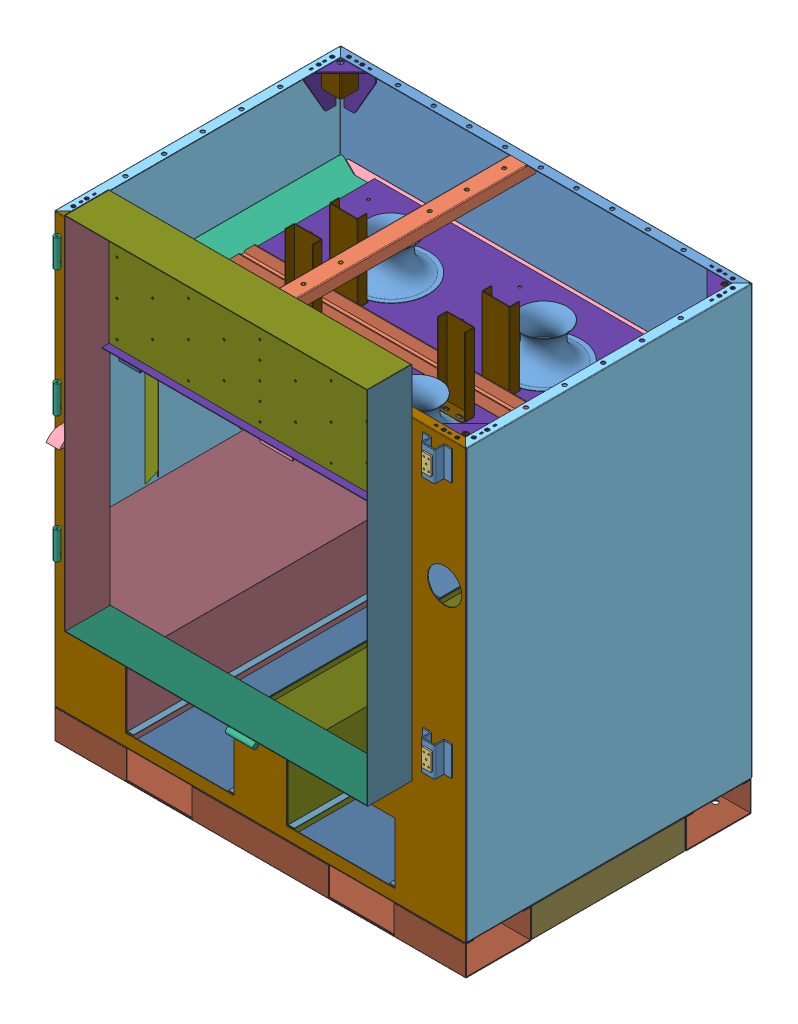
SolidWorks assembly 主機, configuration 預設. Lengths in mm.
Overall size (1423.04 1696.79 1110.69).
127 component instances, 43 part files, 85 mates.
Components (placement in the parent):
- 機體後板-1: 機體後板 [預設] at (-41.0813 66.5472 -21.748) size (1380 1438.1 45.5)
  - LB-A54A-02-6-1: LB-A54A-02-6 [預設] at (-80618.6768 10088.9698 -1) size (1380 1438.1 34.19)
  - LB-A54A-02-7-1: LB-A54A-02-7 [預設] at (654.2438 -32.1294 19.8) x (-1 0 0) z (0 0 -1) size (1360 70.4 18.8)
  - LB-A54-03-4-1: LB-A54-03-4 [預設] at (-510.6908 -452.7134 1) size (443.37 51.57 20.58)
  - LB-A54-03-4-2: LB-A54-03-4 [預設] at (39.1118 -452.7134 1) size (443.37 51.57 20.58)
  - LB-A54A-02-8-1: LB-A54A-02-8 [預設] at (-85867.9995 11163.7201 1) size (1352 43.5 43.5)
- 機體左板-1: 機體左板 [預設] at (-750.0294 157.4231 409.053) x (0 0 -1) z (1 0 0) size (956 1468.3 173.55)
  - LB-A54A-02-25-1: LB-A54A-02-25 [預設] at (-80501.2269 12822.4182 -1) size (956 1468.3 34.19)
  - LB-A54A-02-9-1: LB-A54A-02-9 [預設] at (-520.391 339.3107 -46.78) x (1 0 0) z (0 -1 0) size (948 152.22 53.22)
  - LB-A54A-02-23-1: LB-A54A-02-23 [預設] at (-186.4707 336.0907 45.7599) x (0 -1 0) z (0.707107 0 -0.707107) size (628.6 32.46 32.46)
  - LB-A54A-02-23-2: LB-A54A-02-23 [預設] at (133.5293 336.0907 45.7599) x (0 -1 0) z (0.707107 0 -0.707107) size (628.6 32.46 32.46)
  - LB-A54A-02-24-1: LB-A54A-02-24 [預設] at (-234.3113 -777.1798 45.7599) x (0 1 0) z (-0.707107 0 -0.707107) size (465.6 32.46 32.46)
  - LB-A54A-02-24-2: LB-A54A-02-24 [預設] at (85.6887 -777.1798 45.7599) x (0 1 0) z (-0.707107 0 -0.707107) size (465.6 32.46 32.46)
- LB-A54A-02-1-1: LB-A54A-02-1 [預設] at (631.1626 -630.0662 939.544) x (-1 0 0) z (0 0 -1) size (1380 1440 32.1)
- 機體左板-2: 機體左板 [預設] at (632.3545 157.4231 509.835) x (0 0 1) z (-1 0 0) size (956 1468.3 173.55)
  - LB-A54A-02-25-1: LB-A54A-02-25 [預設] at (-80501.2269 12822.4182 -1) size (956 1468.3 34.19)
  - LB-A54A-02-9-1: LB-A54A-02-9 [預設] at (-520.391 339.3107 -46.78) x (1 0 0) z (0 -1 0) size (948 152.22 53.22)
  - LB-A54A-02-23-1: LB-A54A-02-23 [預設] at (-186.4707 336.0907 45.7599) x (0 -1 0) z (0.707107 0 -0.707107) size (628.6 32.46 32.46)
  - LB-A54A-02-23-2: LB-A54A-02-23 [預設] at (133.5293 336.0907 45.7599) x (0 -1 0) z (0.707107 0 -0.707107) size (628.6 32.46 32.46)
  - LB-A54A-02-24-1: LB-A54A-02-24 [預設] at (-234.3113 -777.1798 45.7599) x (0 1 0) z (-0.707107 0 -0.707107) size (465.6 32.46 32.46)
  - LB-A54A-02-24-2: LB-A54A-02-24 [預設] at (85.6887 -777.1798 45.7599) x (0 1 0) z (-0.707107 0 -0.707107) size (465.6 32.46 32.46)
- 底板-1: 底板 [預設] at (-68.9419 -631.2162 474.3961) x (1 0 0) z (0 -1 0) size (1380.01 960 103.29)
  - LB-A54A-02-26-1: LB-A54A-02-26 [預設] at (-83868.7741 4779.2866 -1.15) size (1380 960 2.3)
  - LB-A54-01-1-1: LB-A54-01-1 [預設] at (-4146.7623 -34163.5866 99.142) size (1380 221 100.99)
  - LB-A54-01-1-2: LB-A54-01-1 [預設] at (4166.9713 34133.8822 99.142) x (-1 0 0) z (0 0 1) size (1380 221 100.99)
  - LB-A54A-02-48-1: LB-A54A-02-48 [預設] at (-5795.5581 81855.4362 102.142) x (0 -1 0) z (0 0 -1) size (517 187 100.99)
  - LB-A54A-02-48-2: LB-A54A-02-48 [預設] at (-5204.2988 81856.4362 102.142) x (0 -1 0) z (0 0 -1) size (517 187 100.99)
  - LB-A54A-02-48-3: LB-A54A-02-48 [預設] at (-4602.5501 81856.4362 102.142) x (0 -1 0) z (0 0 -1) size (517 187 100.99)
- 抽屜導板-1-1: 抽屜導板-1 [預設] at (-629.1921 -325.5931 429.5209) x (0 0 -1) z (1 0 0) size (956 485.93 257.9)
  - LB-A54A-02-27-1: LB-A54A-02-27 [預設] at (-79953.6583 17617.1683 116.5034) size (956 485.93 236.21)
  - LB-A54-10-4-1: LB-A54-10-4 [預設] at (-85291.4913 17401.3144 118.1034) size (955 14.7 21.69)
- 抽屜導板-1-2: 抽屜導板-1 [預設] at (511.5173 -325.5931 484.9831) x (0 0 1) z (-1 0 0) size (956 485.93 257.9)
  - LB-A54A-02-27-1: LB-A54A-02-27 [預設] at (-79953.6583 17617.1683 116.5034) size (956 485.93 236.21)
  - LB-A54-10-4-1: LB-A54-10-4 [預設] at (-85291.4913 17401.3144 118.1034) size (955 14.7 21.69)
- 抽屜導板-2-1: 抽屜導板-2 [預設] at (-103.4633 -459.7341 455.609) x (0 0 1) z (-1 0 0) size (956 387.73 110.27)
  - LB-A54A-02-28-1: LB-A54A-02-28 [預設] at (-81709.8281 17694.6839 42.6882) size (956 387.73 88.58)
  - LB-A54-10-4-1: LB-A54-10-4 [預設] at (-85262.1171 17534.7927 44.2882) size (955 14.7 21.69)
- 抽屜導板-3-1: 抽屜導板-3 [預設] at (-14.2116 -436.2348 485.6989) x (0 0 -1) z (1 0 0) size (956 387.73 110.27)
  - LB-A54A-02-29-1: LB-A54A-02-29 [預設] at (-83501.0241 17671.1846 42.6882) size (956 387.73 88.58)
  - LB-A54-10-4-1: LB-A54-10-4 [預設] at (-85236.3132 17511.2933 44.2882) size (955 14.7 21.69)
- 濾材風箱-1-1: 濾材風箱-1 [預設] at (-7.9679 507.4838 538.2077) x (1 0 0) z (0 1 0) size (1128.4 969.2 262.16)
  - LB-A54A-02-11-1: LB-A54A-02-11 [預設] at (-609.5195 -443.3362 -10.75) size (1128.4 969.2 21.5)
  - LB-A54-07-4-1: LB-A54-07-4 [預設] at (-382.2595 134.0628 -46.99) x (0 0 1) z (0 1 0) size (260.16 94.4 42.16)
  - LB-A54-07-4-2: LB-A54-07-4 [預設] at (129.7405 134.0628 -46.99) x (0 0 1) z (0 1 0) size (260.16 94.4 42.16)
  - LB-A54-07-4-3: LB-A54-07-4 [預設] at (-231.4595 17.0628 -46.99) x (0 0 1) z (0 -1 0) size (260.16 94.4 42.16)
  - LB-A54-07-4-4: LB-A54-07-4 [預設] at (280.5405 17.0628 -46.99) x (0 0 1) z (0 -1 0) size (260.16 94.4 42.16)
  - 250文氏管-1: 250文氏管 [預設] at (-422.6898 248.1172 -8.75) x (0.927762 0.373172 0) z (0.373172 -0.927762 0) size (250 120 250)
  - 250文氏管-2: 250文氏管 [預設] at (90.1102 248.1172 -8.75) x (0.927762 0.373172 0) z (0.373172 -0.927762 0) size (250 120 250)
  - 250文氏管-3: 250文氏管 [預設] at (-422.6898 -178.8828 -8.75) x (0.927762 0.373172 0) z (0.373172 -0.927762 0) size (250 120 250)
  - 250文氏管-4: 250文氏管 [預設] at (90.1102 -178.8828 -8.75) x (0.927762 0.373172 0) z (0.373172 -0.927762 0) size (250 120 250)
  - LB-A54A-02-12-2: LB-A54A-02-12 [預設] at (-84291.9278 16147.3106 -8.75) size (1128.4 55 40.99)
- 凸輪軌道座-中-1: 凸輪軌道座-中 [預設] at (-58.2874 410.5301 355.1892) x (0 0 -1) z (1 0 0) size (856 69.59 110.4)
  - LB-A54-12-2-1: LB-A54-12-2 [預設] at (-530.5548 -8.8562 -24.71) size (856 68.08 109.86)
  - LB-A54-12-8-1: LB-A54-12-8 [預設] at (-530.5548 17.0438 55.01) x (0 0 -1) z (1 0 0) size (110.2 69 3)
  - LB-A54-12-7-2: LB-A54-12-7 [預設] at (325.4452 17.2038 -54.99) x (0 0 1) z (-1 0 0) size (110.2 69 3)
  - LB-A54-12-9-1: LB-A54-12-9 [預設] at (-245.0548 17.4038 52.63) x (0 0 -1) z (1 0 0) size (104.6 66.5 3)
  - LB-A54-12-9-2: LB-A54-12-9 [預設] at (39.9452 17.4038 52.63) x (0 0 -1) z (1 0 0) size (104.6 66.5 3)
  - 2分半點焊螺帽-1: 2分半點焊螺帽 [預設] at (-492.5548 78.7038 0) x (-0.002666 0 -0.999996) z (0.999996 0 -0.002666) size (18.22 7.93 18.22)
  - 2分半點焊螺帽-2: 2分半點焊螺帽 [預設] at (-297.5548 78.7038 0) x (-0.002666 0 -0.999996) z (0.999996 0 -0.002666) size (18.22 7.93 18.22)
  - 2分半點焊螺帽-3: 2分半點焊螺帽 [預設] at (-102.5548 78.7038 0) x (-0.002666 0 -0.999996) z (0.999996 0 -0.002666) size (18.22 7.93 18.22)
  - 2分半點焊螺帽-4: 2分半點焊螺帽 [預設] at (92.4452 78.7038 0) x (-0.002666 0 -0.999996) z (0.999996 0 -0.002666) size (18.22 7.93 18.22)
  - 2分半點焊螺帽-5: 2分半點焊螺帽 [預設] at (287.4452 78.7038 0) x (-0.002666 0 -0.999996) z (0.999996 0 -0.002666) size (18.22 7.93 18.22)
- 凸輪軌道座-左-1: 凸輪軌道座-左 [預設] at (-551.6774 443.4947 508.4972) x (0 0 1) z (-1 0 0) size (856 69.43 71.3)
  - LB-A54-12-1-1: LB-A54-12-1 [預設] at (-478.7533 -41.8208 -5.1) size (856 68.08 70.64)
  - LB-A54-12-4-1: LB-A54-12-4 [預設] at (-478.7533 -15.7608 35.7) x (0 0 -1) z (1 0 0) size (71.3 69 3)
  - LB-A54-12-5-1: LB-A54-12-5 [預設] at (374.2467 -15.7608 35.7) x (0 0 -1) z (1 0 0) size (71.3 69 3)
  - LB-A54-12-6-1: LB-A54-12-6 [預設] at (90.2467 -14.8808 35.4) x (0 0 -1) z (1 0 0) size (68.5 66.5 3)
  - LB-A54-12-6-2: LB-A54-12-6 [預設] at (-194.7533 -14.8808 35.4) x (0 0 -1) z (1 0 0) size (68.5 66.5 3)
  - 2分半點焊螺帽-1: 2分半點焊螺帽 [預設] at (-440.7533 45.7392 15.11) size (18.22 7.93 18.22)
  - 2分半點焊螺帽-2: 2分半點焊螺帽 [預設] at (-245.7533 45.7392 15.11) size (18.22 7.93 18.22)
  - 2分半點焊螺帽-3: 2分半點焊螺帽 [預設] at (-50.7533 45.7392 15.11) size (18.22 7.93 18.22)
  - 2分半點焊螺帽-4: 2分半點焊螺帽 [預設] at (144.2467 45.7392 15.11) size (18.22 7.93 18.22)
  - 2分半點焊螺帽-5: 2分半點焊螺帽 [預設] at (339.2467 45.7392 15.11) size (18.22 7.93 18.22)
- 凸輪軌道座-右-1: 凸輪軌道座-右 [預設] at (435.1026 473.5613 463.8637) x (0 0 -1) z (1 0 0) size (856 69.43 71.7)
  - LB-A54-12-3-1: LB-A54-12-3 [預設] at (-421.8803 -71.8874 -5.1) size (856 68.08 70.64)
  - LB-A54-12-4-1: LB-A54-12-4 [預設] at (431.1197 -45.8274 36.1) x (0 0 -1) z (1 0 0) size (71.3 69 3)
  - LB-A54-12-5-1: LB-A54-12-5 [預設] at (-421.8803 -45.8274 35.7) x (0 0 -1) z (1 0 0) size (71.3 69 3)
  - LB-A54-12-6-1: LB-A54-12-6 [預設] at (147.1197 -44.9474 35.4) x (0 0 -1) z (1 0 0) size (68.5 66.5 3)
  - LB-A54-12-6-2: LB-A54-12-6 [預設] at (-137.8803 -44.9474 35.4) x (0 0 -1) z (1 0 0) size (68.5 66.5 3)
  - 2分半點焊螺帽-1: 2分半點焊螺帽 [預設] at (-383.8803 15.6726 15.11) size (18.22 7.93 18.22)
  - 2分半點焊螺帽-2: 2分半點焊螺帽 [預設] at (-188.8803 15.6726 15.11) size (18.22 7.93 18.22)
  - 2分半點焊螺帽-3: 2分半點焊螺帽 [預設] at (6.1197 15.6726 15.11) size (18.22 7.93 18.22)
  - 2分半點焊螺帽-4: 2分半點焊螺帽 [預設] at (201.1197 15.6726 15.11) size (18.22 7.93 18.22)
  - 2分半點焊螺帽-5: 2分半點焊螺帽 [預設] at (396.1197 15.6726 15.11) size (18.22 7.93 18.22)
- LB-A54A-02-2-1: LB-A54A-02-2 [預設] at (-567.7375 -248.8662 922.444) x (0 1 0) z (1 0 0) size (1212.3 152.4 16.9)
- LB-A54A-02-3-1: LB-A54A-02-3 [預設] at (448.8626 -248.8662 922.444) x (0 1 0) z (1 0 0) size (1212.3 152.4 16.9)
- LB-A54A-02-4-1: LB-A54A-02-4 [預設] at (-565.1374 -246.8662 922.1663) x (1 0 0) z (0 -1 0) size (1014 152.38 17.18)
- LB-A54A-02-5-1: LB-A54A-02-5 [預設] at (-565.1374 515.4561 939.544) size (1014 447.98 148.38)
- 連接補強座-1-1: 連接補強座-1 [預設] at (-753.2212 727.2428 -2.373) x (0 0 -1) z (0 -1 0) size (120.61 124.61 161.4)
  - LB-A54A-02-32-1: LB-A54A-02-32 [預設] at (-84294.0927 8119.5382 -80.691) size (120.61 124.61 161.4)
  - LB-A54-02-5-1: LB-A54-02-5 [預設] at (-51.817 10.2837 -76.691) x (0 1 0) z (1 0 0) size (64.1 80 64.1)
- 連接補強座-1-2: 連接補強座-1 [預設] at (612.9795 727.2428 -24.9398) x (1 0 0) z (0 -1 0) size (120.61 124.61 161.4)
  - LB-A54A-02-32-1: LB-A54A-02-32 [預設] at (-84294.0927 8119.5382 -80.691) size (120.61 124.61 161.4)
  - LB-A54-02-5-1: LB-A54-02-5 [預設] at (-51.817 10.2837 -76.691) x (0 1 0) z (1 0 0) size (64.1 80 64.1)
- 連接補強座-1-3: 連接補強座-1 [預設] at (-730.6544 727.2428 943.8277) x (-1 0 0) z (0 -1 0) size (120.61 124.61 161.4)
  - LB-A54A-02-32-1: LB-A54A-02-32 [預設] at (-84294.0927 8119.5382 -80.691) size (120.61 124.61 161.4)
  - LB-A54-02-5-1: LB-A54-02-5 [預設] at (-51.817 10.2837 -76.691) x (0 1 0) z (1 0 0) size (64.1 80 64.1)
- 連接補強座-1-4: 連接補強座-1 [預設] at (635.5463 727.2428 921.2609) x (0 0 1) z (0 -1 0) size (120.61 124.61 161.4)
  - LB-A54A-02-32-1: LB-A54A-02-32 [預設] at (-84294.0927 8119.5382 -80.691) size (120.61 124.61 161.4)
  - LB-A54-02-5-1: LB-A54-02-5 [預設] at (-51.817 10.2837 -76.691) x (0 1 0) z (1 0 0) size (64.1 80 64.1)
- FE2100LZ-54-47-2-1: FE2100LZ-54-47-2 [預設] at (613.0545 688.8338 974.744) x (-1 0 0) z (0 0 -1) size (97.2 98 35.2)
- FE2100LZ-54-47-2-2: FE2100LZ-54-47-2 [預設] at (613.0545 -171.1662 974.744) x (-1 0 0) z (0 0 -1) size (97.2 98 35.2)
- 機體-補強1-1: 機體-補強1 [預設] at (-132.7621 791.0738 490.8283) x (0 0 -1) z (0 -1 0) size (954 60.44 38.15)
  - LB-A54A-02-43-1: LB-A54A-02-43 [預設] at (-445.6157 -48.5473 -18.86) size (954 60.44 37.72)
  - 2分半點焊螺帽-1: 2分半點焊螺帽 [預設] at (-368.1832 13.9527 -11.36) x (1 0 0) z (0 1 0) size (18.22 7.93 18.22)
  - 2分半點焊螺帽-2: 2分半點焊螺帽 [預設] at (-243.1832 13.9527 -11.36) x (1 0 0) z (0 1 0) size (18.22 7.93 18.22)
  - 2分半點焊螺帽-3: 2分半點焊螺帽 [預設] at (-118.1832 13.9527 -11.36) x (1 0 0) z (0 1 0) size (18.22 7.93 18.22)
  - 2分半點焊螺帽-4: 2分半點焊螺帽 [預設] at (430.9519 13.9527 -11.36) x (1 0 0) z (0 1 0) size (18.22 7.93 18.22)
  - 2分半點焊螺帽-5: 2分半點焊螺帽 [預設] at (305.9519 13.9527 -11.36) x (1 0 0) z (0 1 0) size (18.22 7.93 18.22)
  - 2分半點焊螺帽-6: 2分半點焊螺帽 [預設] at (180.9519 13.9527 -11.36) x (1 0 0) z (0 1 0) size (18.22 7.93 18.22)
- LB-A54A-02-30-1: LB-A54A-02-30 [預設] at (555.7545 768.3338 979.744) x (0 -1 0) z (0 0 -1) size (61 33 5)
- LB-A54A-02-30-2: LB-A54A-02-30 [預設] at (555.7545 -91.6662 979.744) x (0 -1 0) z (0 0 -1) size (61 33 5)
- 撐座1-1: 撐座1 [預設] at (-671.5374 -29294.2198 153782.015) x (0 0 -1) z (1 0 0) size (106.64 28 45)
- LB-A54-02-3-3: LB-A54-02-3 [預設] at (-510.0888 -368.0662 937.544) x (1 0 0) z (0 0 -1) size (363 19.1 19.1)
- LB-A54-02-3-4: LB-A54-02-3 [預設] at (30.4138 -368.0662 937.544) x (1 0 0) z (0 0 -1) size (363 19.1 19.1)
- 釘雙座-1: 釘雙座 [預設] at (-659.4122 755.0376 966.2275) size (19.4 93 19.4)
  - 門蓋丁雙固定座-1: 門蓋丁雙固定座 [預設] at (-112.9585 -46.1037 23.6835) (suppressed, hidden)
  - 釘雙-1: 釘雙 [預設] at (-19.1747 49.3962 36.1835) x (0.021323 0 -0.999773) z (0 -1 0) size (19 19 93)
- 釘雙座-2: 釘雙座 [預設] at (-659.4122 330.0376 966.2275) size (19.4 93 19.4)
  - 門蓋丁雙固定座-1: 門蓋丁雙固定座 [預設] at (-112.9585 -46.1037 23.6835) (suppressed, hidden)
  - 釘雙-1: 釘雙 [預設] at (-19.1747 49.3962 36.1835) x (0.021323 0 -0.999773) z (0 -1 0) size (19 19 93)
- 釘雙座-3: 釘雙座 [預設] at (-659.4122 -94.9624 966.2275) size (19.4 93 19.4)
  - 門蓋丁雙固定座-1: 門蓋丁雙固定座 [預設] at (-112.9585 -46.1037 23.6835) (suppressed, hidden)
  - 釘雙-1: 釘雙 [預設] at (-19.1747 49.3962 36.1835) x (0.021323 0 -0.999773) z (0 -1 0) size (19 19 93)
- 釘雙座-4: 釘雙座 [預設] at (-54.1412 -327.7751 966.2275) x (0 1 0) z (0 0 1) size (19.4 93 19.4)
  - 門蓋丁雙固定座-1: 門蓋丁雙固定座 [預設] at (-112.9585 -46.1037 23.6835) (suppressed, hidden)
  - 釘雙-1: 釘雙 [預設] at (-19.1747 49.3962 36.1835) x (0.021323 0 -0.999773) z (0 -1 0) size (19 19 93)
Mates (geometry in assembly coordinates):
- 重合/共線/共點1: coincident aligned: plane of 機體後板-1/LB-A54A-02-6-1 through (-748.8374 809.9338 -1456.856) normal (0 1 0); plane of 機體左板-1/LB-A54A-02-25-1 through (-2185.1374 809.9338 937.444) normal (0 1 0)
- 重合/共線/共點2: coincident anti-aligned: plane of 機體後板-1/LB-A54A-02-6-1 through (-716.8374 807.9338 11.444) normal (-0.707107 0 0.707107); plane of 機體左板-1/LB-A54A-02-25-1 through (-716.8374 807.9338 11.444) normal (0.707107 0 -0.707107)
- 重合/共線/共點3: coincident: line of 機體後板-1/LB-A54A-02-6-1 through (-716.8374 807.9338 11.444) axis (0 1 0); point of 機體左板-1/LB-A54A-02-25-1
- 重合/共線/共點4: coincident aligned: plane of 機體左板-1/LB-A54A-02-25-1 through (-2185.1374 809.9338 937.444) normal (0 1 0); plane of LB-A54A-02-1-1 through (626.1626 809.9338 938.144) normal (0 1 0)
- 重合/共線/共點5: coincident anti-aligned: plane of 機體左板-1/LB-A54A-02-25-1 through (-716.8374 807.9338 907.444) normal (0.707107 0 0.707107); plane of LB-A54A-02-1-1 through (-746.5374 807.9338 937.144) normal (-0.707107 0 -0.707107)
- 重合/共線/共點6: coincident: line of 機體左板-1/LB-A54A-02-25-1 through (-746.5374 807.9338 937.144) axis (0 1 0); point of LB-A54A-02-1-1
- 重合/共線/共點7: coincident aligned: plane of 機體後板-1/LB-A54A-02-6-1 through (-748.8374 809.9338 -1456.856) normal (0 1 0); plane of 機體左板-2/LB-A54A-02-25-1 through (2067.4625 809.9338 -18.556) normal (0 1 0)
- 重合/共線/共點8: coincident anti-aligned: plane of 機體後板-1/LB-A54A-02-6-1 through (599.1625 807.9338 11.444) normal (0.707107 0 0.707107); plane of 機體左板-2/LB-A54A-02-25-1 through (599.1625 807.9338 11.444) normal (-0.707107 0 -0.707107)
- 重合/共線/共點9: coincident: line of 機體後板-1/LB-A54A-02-6-1 through (599.1625 807.9338 11.444) axis (0 1 0); point of 機體左板-2/LB-A54A-02-25-1
- 重合/共線/共點10: coincident anti-aligned: plane of LB-A54A-02-1-1 through (631.1626 -630.0662 937.544) normal (0 -1 0); plane of 底板-1/LB-A54A-02-26-1 through (-748.8374 -630.0662 -20.456) normal (0 1 0)
- 重合/共線/共點11: coincident aligned: plane of LB-A54A-02-1-1 through (626.1626 807.5338 939.544) normal (0 0 1); plane of 底板-1/LB-A54A-02-26-1 through (631.1626 -632.3662 939.544) normal (0 0 1)
- 重合/共線/共點12: coincident aligned: plane of 機體後板-1/LB-A54A-02-6-1 through (-748.8374 -628.1662 -20.748) normal (-1 0 0); plane of 底板-1/LB-A54A-02-26-1 through (-748.8374 -632.3662 939.544) normal (-1 0 0)
- 重合/共線/共點13: coincident anti-aligned: plane of 機體後板-1/LB-A54A-02-6-1 through (-748.8374 -628.1662 -20.748) normal (0 0 1); plane of 抽屜導板-1-1/LB-A54A-02-27-1 through (-511.0887 -377.7495 -20.748) normal (0 0 -1)
- 重合/共線/共點14: coincident: line of 機體後板-1/LB-A54A-02-6-1 through (-745.7061 -142.1322 -22.748) axis (0.707107 -0.707107 0); plane of 抽屜導板-1-1/LB-A54A-02-27-1 through (-512.0195 -375.8188 -20.748) normal (0.707107 0.707107 0)
- 重合/共線/共點15: coincident: line of 機體後板-1/LB-A54A-02-6-1 through (-511.0887 -376.7495 -22.748) axis (0 -1 0); plane of 抽屜導板-1-1/LB-A54A-02-27-1 through (-511.0887 -376.7495 -20.748) normal (1 0 0)
- 重合/共線/共點16: coincident anti-aligned: plane of 機體後板-1/LB-A54A-02-6-1 through (-748.8374 -628.1662 -20.748) normal (0 0 1); plane of 抽屜導板-1-2/LB-A54A-02-27-1 through (624.9578 -145.2056 -20.748) normal (0 0 -1)
- 重合/共線/共點17: coincident: line of 機體後板-1/LB-A54A-02-6-1 through (628.0312 -142.1322 -22.748) axis (-0.707107 -0.707107 0); plane of 抽屜導板-1-2/LB-A54A-02-27-1 through (394.3446 -375.8188 935.252) normal (-0.707107 0.707107 0)
- 重合/共線/共點18: coincident: line of 機體後板-1/LB-A54A-02-6-1 through (393.4139 -376.7495 -22.748) axis (0 -1 0); plane of 抽屜導板-1-2/LB-A54A-02-27-1 through (393.4139 -376.7495 935.252) normal (-1 0 0)
- 重合/共線/共點19: coincident anti-aligned: plane of 機體後板-1/LB-A54A-02-6-1 through (-748.8374 -628.1662 -20.748) normal (0 0 1); plane of 抽屜導板-2-1/LB-A54A-02-28-1 through (-61.3451 -291.0059 -20.748) normal (0 0 -1)
- 重合/共線/共點20: coincident: line of 機體後板-1/LB-A54A-02-6-1 through (-147.0887 -376.7495 -22.748) axis (0.707107 0.707107 0); plane of 抽屜導板-2-1/LB-A54A-02-28-1 through (-60.638 -290.2988 935.252) normal (-0.707107 0.707107 0)
- 重合/共線/共點25: coincident: line of 機體後板-1/LB-A54A-02-6-1 through (-167.0887 -588.2662 -22.748) axis (1 0 0); plane of 抽屜導板-2-1/LB-A54-10-4-1 through (-150.9435 -588.2662 935.252) normal (0 1 0)
- 重合/共線/共點26: coincident anti-aligned: plane of 機體後板-1/LB-A54A-02-6-1 through (-748.8374 -628.1662 -20.748) normal (0 0 1); plane of 抽屜導板-3-1/LB-A54A-02-29-1 through (-56.3297 -291.0059 -20.748) normal (0 0 -1)
- 重合/共線/共點27: coincident: line of 機體後板-1/LB-A54A-02-6-1 through (-58.8374 -288.4982 -22.748) axis (0.707107 -0.707107 0); plane of 抽屜導板-3-1/LB-A54A-02-29-1 through (-57.0368 -290.2988 -20.748) normal (0.707107 0.707107 0)
- 重合/共線/共點30: coincident: line of 機體後板-1/LB-A54A-02-6-1 through (49.4139 -588.2662 -22.748) axis (-1 0 0); plane of 抽屜導板-3-1/LB-A54-10-4-1 through (33.2686 -588.2662 -19.748) normal (0 1 0)
- 重合/共線/共點32: coincident anti-aligned: plane of 機體後板-1/LB-A54A-02-8-1 through (-46.8374 496.7338 -729.252) normal (0 1 0); plane of 濾材風箱-1-1/LB-A54A-02-11-1 through (502.9126 496.7338 935.144) normal (0 -1 0)
- 重合/共線/共點33: coincident anti-aligned: plane of LB-A54A-02-1-1 through (626.1626 807.5338 937.544) normal (0 0 -1); plane of 濾材風箱-1-1/LB-A54A-02-11-1 through (502.9126 498.1338 937.544) normal (0 0 1)
- 重合/共線/共點38: coincident anti-aligned: plane of LB-A54A-02-1-1 through (626.1626 807.5338 937.544) normal (0 0 -1); plane of LB-A54A-02-2-1 through (-565.3375 493.8338 937.544) normal (0 0 1)
- 重合/共線/共點39: coincident anti-aligned: plane of LB-A54A-02-1-1 through (-567.7375 516.1338 937.544) normal (1 0 0); plane of LB-A54A-02-2-1 through (-567.7375 493.8338 939.744) normal (-1 0 0)
- 重合/共線/共點41: coincident anti-aligned: plane of LB-A54A-02-1-1 through (626.1626 807.5338 937.544) normal (0 0 -1); plane of LB-A54A-02-3-1 through (448.4626 493.8338 937.544) normal (0 0 1)
- 重合/共線/共點42: coincident anti-aligned: plane of LB-A54A-02-1-1 through (450.8626 -248.8662 937.544) normal (-1 0 0); plane of LB-A54A-02-3-1 through (450.8626 493.8338 939.744) normal (1 0 0)
- 重合/共線/共點43: coincident anti-aligned: plane of LB-A54A-02-1-1 through (-567.7375 -248.8662 937.544) normal (0 1 0); plane of LB-A54A-02-4-1 through (448.8626 -248.8662 1087.9216) normal (0 -1 0)
- 重合/共線/共點44: coincident anti-aligned: plane of LB-A54A-02-1-1 through (626.1626 807.5338 937.544) normal (0 0 -1); plane of LB-A54A-02-4-1 through (448.8626 -98.2886 937.544) normal (0 0 1)
- 重合/共線/共點45: coincident anti-aligned: plane of LB-A54A-02-1-1 through (-567.7375 -248.8662 937.544) normal (0 1 0); plane of LB-A54A-02-3-1 through (450.8626 -248.8662 922.444) normal (0 -1 0)
- 重合/共線/共點46: coincident anti-aligned: plane of LB-A54A-02-3-1 through (448.8626 493.8338 939.744) normal (-1 0 0); plane of LB-A54A-02-4-1 through (448.8626 -248.8662 922.1663) normal (1 0 0)
- 重合/共線/共點47: coincident anti-aligned: plane of LB-A54A-02-1-1 through (-567.7375 -248.8662 937.544) normal (0 1 0); plane of LB-A54A-02-2-1 through (-565.7375 -248.8662 922.444) normal (0 -1 0)
- 重合/共線/共點51: coincident anti-aligned: plane of 機體左板-1/LB-A54A-02-25-1 through (-2185.1374 807.9338 937.444) normal (0 -1 0); plane of 連接補強座-1-1/LB-A54A-02-32-1 through (-743.4374 807.9338 0.444) normal (0 1 0)
- 同軸心7: concentric aligned: cylinder of 機體後板-1/LB-A54A-02-6-1 through (-703.8374 807.9338 -3.556) axis (0 1 0) radius 6.5; cylinder of 連接補強座-1-1/LB-A54A-02-32-1 through (-703.8374 803.9338 -3.556) axis (0 1 0) radius 4.1
- 同軸心8: concentric aligned: cylinder of 機體後板-1/LB-A54A-02-6-1 through (-658.8374 807.9338 -3.556) axis (0 1 0) radius 6.5; cylinder of 連接補強座-1-1/LB-A54A-02-32-1 through (-658.8374 803.9338 -3.556) axis (0 1 0) radius 4.1
- 重合/共線/共點52: coincident anti-aligned: plane of 機體後板-1/LB-A54A-02-6-1 through (-748.8374 807.9338 -1456.856) normal (0 -1 0); plane of 連接補強座-1-2/LB-A54A-02-32-1 through (610.1625 807.9338 -15.156) normal (0 1 0)
- 同軸心9: concentric aligned: cylinder of 機體左板-2/LB-A54A-02-25-1 through (614.1625 807.9338 24.444) axis (0 1 0) radius 6.5; cylinder of 連接補強座-1-2/LB-A54A-02-32-1 through (614.1625 803.9338 24.444) axis (0 1 0) radius 4.1
- 同軸心10: concentric aligned: cylinder of 機體左板-2/LB-A54A-02-25-1 through (614.1625 807.9338 69.444) axis (0 1 0) radius 6.5; cylinder of 連接補強座-1-2/LB-A54A-02-32-1 through (614.1625 803.9338 69.444) axis (0 1 0) radius 4.1
- 重合/共線/共點53: coincident anti-aligned: plane of 機體左板-2/LB-A54A-02-25-1 through (2067.4625 807.9338 -18.556) normal (0 -1 0); plane of 連接補強座-1-3/LB-A54A-02-32-1 through (-727.8374 807.9338 934.044) normal (0 1 0)
- 同軸心11: concentric aligned: cylinder of 機體左板-1/LB-A54A-02-25-1 through (-731.8374 807.9338 894.444) axis (0 1 0) radius 6.5; cylinder of 連接補強座-1-3/LB-A54A-02-32-1 through (-731.8374 803.9338 894.444) axis (0 1 0) radius 4.1
- 同軸心12: concentric aligned: cylinder of 機體左板-1/LB-A54A-02-25-1 through (-731.8374 807.9338 849.444) axis (0 1 0) radius 6.5; cylinder of 連接補強座-1-3/LB-A54A-02-32-1 through (-731.8374 803.9338 849.444) axis (0 1 0) radius 4.1
- 重合/共線/共點54: coincident anti-aligned: plane of LB-A54A-02-1-1 through (626.1626 807.9338 938.144) normal (0 -1 0); plane of 連接補強座-1-4/LB-A54A-02-32-1 through (625.7626 807.9338 918.444) normal (0 1 0)
- 同軸心13: concentric aligned: cylinder of LB-A54A-02-1-1 through (586.1626 807.9338 922.444) axis (0 1 0) radius 6.5; cylinder of 連接補強座-1-4/LB-A54A-02-32-1 through (586.1626 803.9338 922.444) axis (0 1 0) radius 4.1
- 同軸心14: concentric aligned: cylinder of LB-A54A-02-1-1 through (541.1626 807.9338 922.444) axis (0 1 0) radius 6.5; cylinder of 連接補強座-1-4/LB-A54A-02-32-1 through (541.1626 803.9338 922.444) axis (0 1 0) radius 4.1
- 重合/共線/共點55: coincident anti-aligned: plane of LB-A54A-02-1-1 through (626.1626 807.5338 939.544) normal (0 0 1); plane of FE2100LZ-54-47-2-1 through (587.8545 786.8338 939.544) normal (0 0 -1)
- 平行相距1: distance = 23.1 mm aligned: plane of FE2100LZ-54-47-2-1 through (440.2545 786.8338 939.544) normal (0 1 0); plane of LB-A54A-02-1-1 through (626.1626 809.9338 938.144) normal (0 1 0)
- 平行相距2: distance = 45.5 mm aligned: plane of 機體左板-2/LB-A54A-02-25-1 through (633.3545 -628.1662 -18.556) normal (1 0 0); plane of FE2100LZ-54-47-2-1 through (587.8545 786.8338 939.544) normal (1 0 0)
- 重合/共線/共點64: coincident anti-aligned: plane of LB-A54A-02-1-1 through (-716.8374 807.9338 907.444) normal (0 0 -1); plane of 機體-補強1-1/LB-A54A-02-43-1 through (-91.8094 806.9338 907.444) normal (0 0 1)
- 重合/共線/共點65: coincident aligned: plane of LB-A54A-02-1-1 through (626.1626 809.9338 938.144) normal (0 1 0); plane of 機體-補強1-1/LB-A54A-02-43-1 through (-85.8094 809.9338 -12.556) normal (0 1 0)
- 平行相距6: distance = 600 mm anti-aligned: plane of 機體左板-1/LB-A54A-02-25-1 through (-749.0294 -628.1662 937.444) normal (1 0 0); plane of 機體-補強1-1/LB-A54A-02-43-1 through (-149.0294 867.7138 -12.556) normal (-1 0 0)
- 重合/共線/共點67: coincident anti-aligned: plane of FE2100LZ-54-47-2-1 through (613.0545 786.8338 974.744) normal (0 0 1); plane of LB-A54A-02-30-1 through (525.7545 710.3338 974.744) normal (0 0 -1)
- 同軸心19: concentric aligned: cylinder of FE2100LZ-54-47-2-1 through (531.2545 756.3338 970.744) axis (0 0 1) radius 2.65; cylinder of LB-A54A-02-30-1 through (531.2545 756.3338 974.744) axis (0 0 1) radius 2.65
- 同軸心20: concentric aligned: cylinder of FE2100LZ-54-47-2-1 through (547.2545 756.3338 970.744) axis (0 0 1) radius 2.65; cylinder of LB-A54A-02-30-1 through (547.2545 756.3338 974.744) axis (0 0 1) radius 2.65
- 重合/共線/共點71: coincident anti-aligned: plane of LB-A54A-02-1-1 through (626.1626 807.5338 939.544) normal (0 0 1); plane of 撐座1-1 through (-626.5374 153.1797 939.544) normal (0 0 -1)
- 平行相距7: distance = 77.3 mm: plane of 撐座1-1 through (-671.5374 153.1797 993.0247) normal (-1 0 0); line of LB-A54A-02-1-1 through (-748.8374 -630.0662 939.544) axis (0 1 0)
- 平行相距9: distance = 4 mm: plane of ?; line of 撐座1-1 through (-626.5374 256.4338 939.544) axis (-1 0 0)
- 重合/共線/共點86: coincident anti-aligned: plane of LB-A54A-02-1-1 through (-147.0887 -385.1662 937.544) normal (0 -1 0); plane of LB-A54-02-3-3 through (-507.0888 -385.1662 936.144) normal (0 1 0)
- 重合/共線/共點88: coincident anti-aligned: plane of LB-A54A-02-1-1 through (-147.0887 -590.1662 937.544) normal (-1 0 0); plane of LB-A54-02-3-3 through (-147.0887 -385.1662 935.144) normal (1 0 0)
- 重合/共線/共點90: coincident anti-aligned: plane of LB-A54A-02-1-1 through (393.4139 -385.1662 937.544) normal (0 -1 0); plane of LB-A54-02-3-4 through (33.4138 -385.1662 936.144) normal (0 1 0)
- 重合/共線/共點91: coincident anti-aligned: plane of LB-A54A-02-1-1 through (393.4139 -590.1662 937.544) normal (-1 0 0); plane of LB-A54-02-3-4 through (393.4139 -385.1662 935.144) normal (1 0 0)
- 重合/共線/共點92: coincident: line of 濾材風箱-1-1/LB-A54A-02-11-1 through (448.8626 516.2338 965.644) axis (0 0 -1); plane of LB-A54A-02-3-1 through (448.8626 493.8338 939.744) normal (-1 0 0)
- 重合/共線/共點93: coincident anti-aligned: plane of LB-A54A-02-1-1 through (626.1626 807.5338 939.544) normal (0 0 1); plane of LB-A54A-02-5-1 through (-565.1374 1108.0114 939.544) normal (0 0 -1)
- 重合/共線/共點94: coincident aligned: plane of LB-A54A-02-3-1 through (450.8626 963.4338 939.744) normal (0 1 0); plane of LB-A54A-02-5-1 through (-565.1374 963.4338 1087.9216) normal (0 1 0)
- 重合/共線/共點95: coincident anti-aligned: plane of LB-A54A-02-3-1 through (448.8626 493.8338 939.744) normal (-1 0 0); plane of LB-A54A-02-5-1 through (448.8626 961.4338 495.3663) normal (1 0 0)
- 重合/共線/共點96: coincident anti-aligned: plane of 濾材風箱-1-1/LB-A54A-02-11-1 through (502.9126 496.7338 935.144) normal (0 -1 0); plane of 凸輪軌道座-中-1/LB-A54-12-2-1 through (-81.0374 496.7338 882.744) normal (0 1 0)
- 同軸心21: concentric anti-aligned: cylinder of 濾材風箱-1-1/LB-A54A-02-11-1 through (-58.2874 498.7338 847.744) axis (0 -1 0) radius 4.5; cylinder of 凸輪軌道座-中-1/LB-A54-12-2-1 through (-58.2874 494.4338 847.744) axis (0 1 0) radius 6.6
- 同軸心22: concentric anti-aligned: cylinder of 濾材風箱-1-1/LB-A54A-02-11-1 through (-58.2874 498.7338 67.744) axis (0 -1 0) radius 4.5; cylinder of 凸輪軌道座-中-1/LB-A54-12-2-1 through (-58.2874 494.4338 67.744) axis (0 1 0) radius 6.6
- 重合/共線/共點97: coincident anti-aligned: plane of 濾材風箱-1-1/LB-A54A-02-11-1 through (502.9126 496.7338 935.144) normal (0 -1 0); plane of 凸輪軌道座-右-1/LB-A54-12-3-1 through (431.9626 496.7338 882.744) normal (0 1 0)
- 同軸心23: concentric anti-aligned: cylinder of 濾材風箱-1-1/LB-A54A-02-11-1 through (450.2126 498.7338 847.744) axis (0 -1 0) radius 4.5; cylinder of 凸輪軌道座-右-1/LB-A54-12-3-1 through (450.2126 494.4338 847.744) axis (0 1 0) radius 6.6
- 同軸心24: concentric anti-aligned: cylinder of 濾材風箱-1-1/LB-A54A-02-11-1 through (450.2126 498.7338 67.744) axis (0 -1 0) radius 4.5; cylinder of 凸輪軌道座-右-1/LB-A54-12-3-1 through (450.2126 494.4338 67.744) axis (0 1 0) radius 6.6
- 重合/共線/共點98: coincident anti-aligned: plane of 濾材風箱-1-1/LB-A54A-02-11-1 through (502.9126 496.7338 935.144) normal (0 -1 0); plane of 凸輪軌道座-左-1/LB-A54-12-1-1 through (-548.5374 496.7338 32.744) normal (0 1 0)
- 同軸心25: concentric anti-aligned: cylinder of 濾材風箱-1-1/LB-A54A-02-11-1 through (-566.7874 498.7338 847.744) axis (0 -1 0) radius 4.5; cylinder of 凸輪軌道座-左-1/LB-A54-12-1-1 through (-566.7874 494.4338 847.744) axis (0 1 0) radius 6.6
- 同軸心26: concentric anti-aligned: cylinder of 濾材風箱-1-1/LB-A54A-02-11-1 through (-566.7874 498.7338 67.744) axis (0 -1 0) radius 4.5; cylinder of 凸輪軌道座-左-1/LB-A54-12-1-1 through (-566.7874 494.4338 67.744) axis (0 1 0) radius 6.6
- 重合/共線/共點99: coincident: line of LB-A54A-02-1-1 through (-147.0887 -590.1662 937.544) axis (-1 0 0); plane of LB-A54-02-3-3 through (-507.0888 -384.7662 937.544) normal (0 0 1)
- 重合/共線/共點100: coincident: line of LB-A54A-02-1-1 through (29.4139 -385.1662 937.544) axis (1 0 0); plane of LB-A54-02-3-4 through (33.4138 -384.7662 937.544) normal (0 0 1)
- 重合/共線/共點101: coincident anti-aligned: plane of LB-A54A-02-1-1 through (626.1626 807.5338 939.544) normal (0 0 1); plane of 釘雙座-1/門蓋丁雙固定座-1 through (-538.7374 708.9338 939.544) normal (0 0 -1)
- 平行相距10: distance = 3 mm aligned: plane of 釘雙座-1/門蓋丁雙固定座-1 through (-655.9869 806.9338 1104.1275) normal (0 1 0); plane of LB-A54A-02-1-1 through (626.1626 809.9338 938.144) normal (0 1 0)
- 平行相距12: distance = 22.5 mm: plane of 釘雙座-1/門蓋丁雙固定座-1; line of LB-A54A-02-1-1 through (-748.8374 -630.0662 939.544) axis (0 1 0)
- 重合/共線/共點102: coincident anti-aligned: plane of LB-A54A-02-1-1 through (626.1626 807.5338 939.544) normal (0 0 1); plane of 釘雙座-4/門蓋丁雙固定座-1 through (-8.0374 -299.1662 939.544) normal (0 0 -1)
- 平行相距13: distance = 642.8 mm: line of LB-A54A-02-1-1 through (-748.8374 -630.0662 939.544) axis (0 1 0); plane of 釘雙座-4/門蓋丁雙固定座-1 through (-106.0374 -486.7662 942.544) normal (-1 0 0)
- 平行相距14: distance = 50.3 mm: plane of 釘雙座-4/門蓋丁雙固定座-1 through (-8.0374 -299.1662 942.544) normal (0 1 0); line of LB-A54A-02-1-1 through (450.8626 -248.8662 939.544) axis (-1 0 0)
- 局部直線複製2: unknown: line of LB-A54A-02-1-1 through (-748.8374 -630.0662 939.544) axis (0 1 0)
